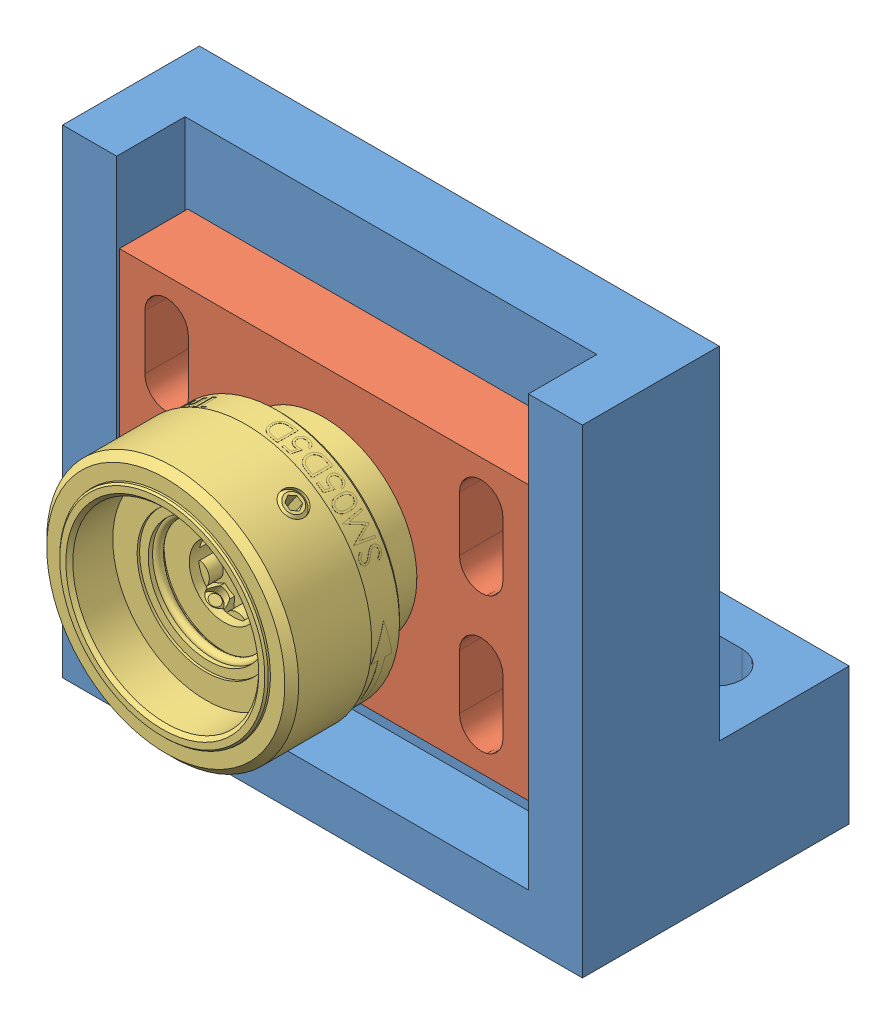
SolidWorks assembly iris_assem, configuration Default. Lengths in mm.
Overall size (38 35 31.31).
3 component instances, 3 part files, 3 mates.
Components (placement in the parent):
- aperture_stand-1: aperture_stand [Default] at (24.6565 7.4152 58.0556) size (38 35 19.5)
- pinhole plate-1: pinhole plate [Default] at (8.8041 16.6677 31.9348) size (29.9 20 5)
- iris_SM05D5D-Solidworks-1: iris_SM05D5D-Solidworks [Web Assembly] at (17.5327 26.6677 41.9579) x (0.828172 -0.560474 0) z (0 0 -1) size (18.41 18.41 12.06)
Mates (geometry in assembly coordinates):
- Coincident1: coincident anti-aligned: plane of aperture_stand-1 through (-1.5673 -31.7543 28.4997) normal (0 0 1); plane of pinhole plate-1 through (2.5827 36.6677 28.4997) normal (0 0 -1)
- Coincident2: coincident aligned: circle of pinhole plate-1; circle of iris_SM05D5D-Solidworks-1
- Coincident3: coincident anti-aligned: plane of aperture_stand-1 through (32.4827 7.4152 -19.9971) normal (-1 0 0); plane of pinhole plate-1 through (32.4827 36.6677 28.4997) normal (1 0 0)
